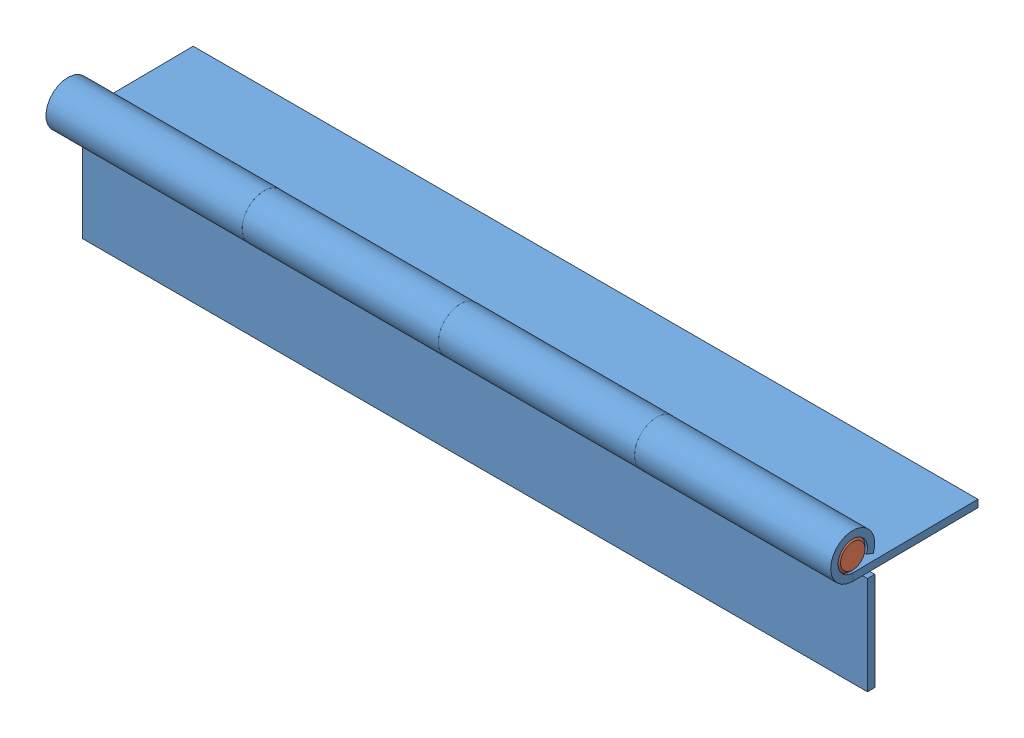
SolidWorks assembly BASE-Cabinet Hinge, configuration Default. Lengths in mm.
Overall size (160 30.24 30.08).
3 component instances, 2 part files, 4 mates.
Components (placement in the parent):
- BASE-Cabinet Hinge Flange-1: BASE-Cabinet Hinge Flange [Default] at (-155.1002 71.3389 114.9534) size (160 30 9)
- BASE-Cabinet Hinge Flange-2: BASE-Cabinet Hinge Flange [Default] at (4.8998 94.0777 92.4265) x (-1 0 0) z (0 0.999956 0.009359) size (160 30 9)
- BASE-Cabinet Hinge Pin-2: BASE-Cabinet Hinge Pin [Default] at (-155.1002 93.2182 117.9534) x (0 0 -1) z (1 0 0) size (6 6 160)
Mates (geometry in assembly coordinates):
- Concentric1: concentric: cylinder of assembly; cylinder of assembly; cylinder of BASE-Cabinet Hinge Flange-2 through (4.8998 96.8389 117.9534) axis (1 0 0) radius 3; cylinder of BASE-Cabinet Hinge Pin-2 through (4.8998 96.8389 117.9534) axis (-1 0 0) radius 3
- Coincident1: coincident: plane of assembly; plane of assembly; plane of BASE-Cabinet Hinge Flange-2 through (4.8998 96.8389 117.9534) normal (1 0 0); plane of BASE-Cabinet Hinge Pin-2 through (4.8998 96.8389 117.9534) normal (1 0 0)
- Concentric2: concentric: cylinder of assembly; cylinder of assembly; cylinder of BASE-Cabinet Hinge Flange-1 through (-75.1002 96.8389 117.9534) axis (-1 0 0) radius 3; cylinder of BASE-Cabinet Hinge Pin-2 through (4.8998 96.8389 117.9534) axis (-1 0 0) radius 3
- Coincident2: coincident: plane of assembly; plane of assembly; plane of BASE-Cabinet Hinge Flange-1 through (-35.1002 96.8389 117.9534) normal (1 0 0); plane of BASE-Cabinet Hinge Flange-2 through (-35.1002 96.8389 117.9534) normal (-1 0 0)
